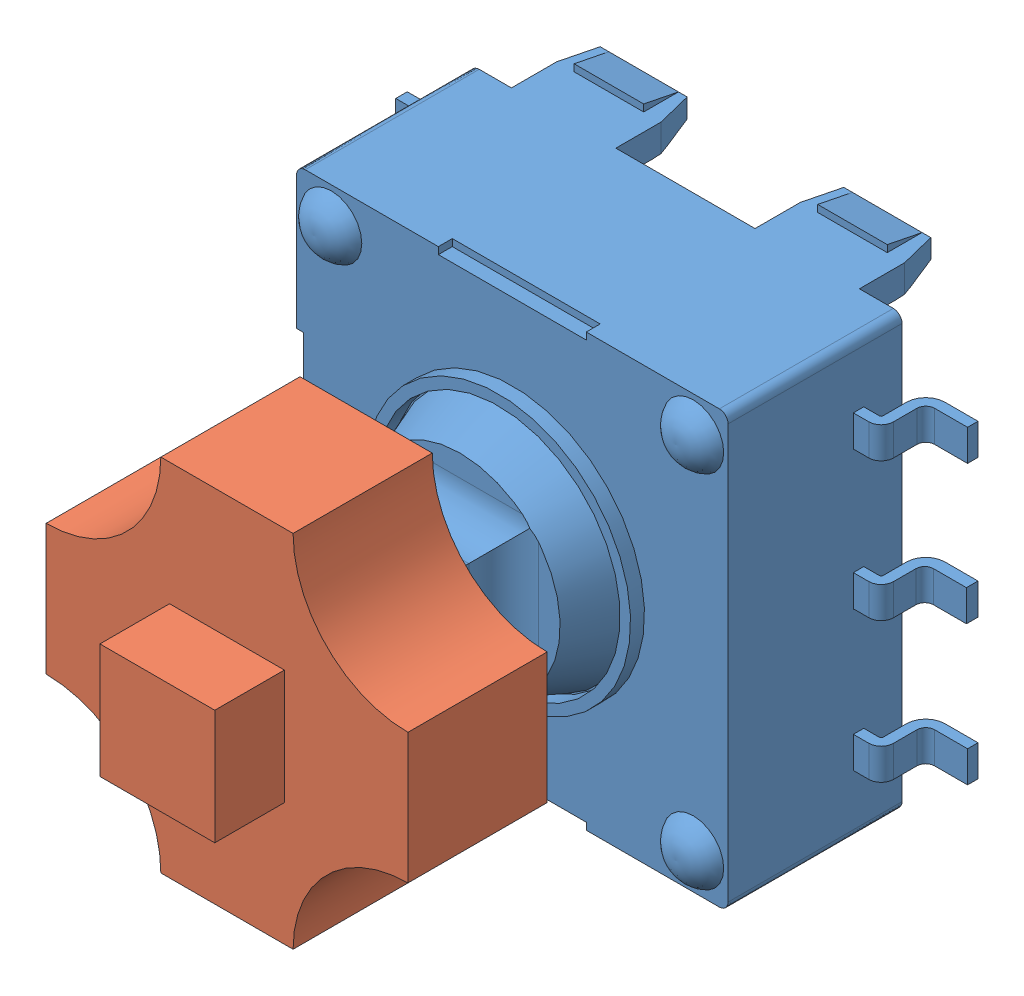
SolidWorks assembly Assem1, configuration Default. Lengths in mm.
Overall size (16.4 12.8 17.5).
2 component instances, 2 part files, 0 mates.
Components (placement in the parent):
- JS5208.step-1: JS5208.step [Default] at (4.4915 6.4734 12.2152) size (16.4 12.8 14.5)
- KeyCap-1: KeyCap [Default] at (0 0 22.1152) size (10.4 10.35 6)
